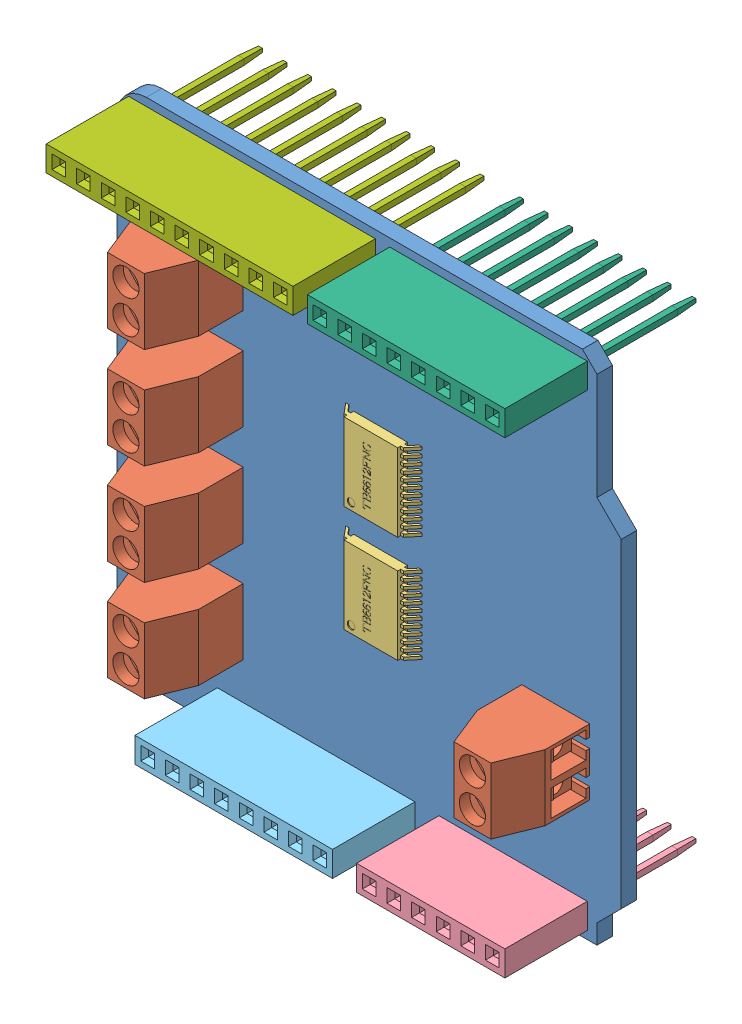
SolidWorks assembly Shield Quad Motor driver TB6612FNG, configuration Défaut. Lengths in mm.
Overall size (52 52.5 20.9).
12 component instances, 7 part files, 33 mates.
Components (placement in the parent):
- Shield Quad Motor - plaque-1: Shield Quad Motor - plaque [Défaut] at (1.0198 -6.275 51.7045) size (52 52.5 1.6)
- bornier double-1: bornier double [Défaut] at (-20.6895 19.3651 53.3045) x (0 -1 0) z (-1 0 0) size (6.8 12.2 7)
- bornier double-2: bornier double [Défaut] at (-20.6895 8.9651 53.3045) x (0 -1 0) z (-1 0 0) size (6.8 12.2 7)
- bornier double-3: bornier double [Défaut] at (-20.6895 -1.4349 53.3045) x (0 -1 0) z (-1 0 0) size (6.8 12.2 7)
- bornier double-4: bornier double [Défaut] at (-20.6895 -11.8349 53.3045) x (0 -1 0) z (-1 0 0) size (6.8 12.2 7)
- bornier double-5: bornier double [Défaut] at (22.0605 -13.2893 53.3045) x (0 1 0) z (1 0 0) size (6.8 12.2 7)
- Microcontroller TB6612FNG-1: Microcontroller TB6612FNG [Défaut] at (0.8257 5.6107 53.6445) x (0 1 0) z (0 0 1) size (8 8.26 1.72)
- Microcontroller TB6612FNG-2: Microcontroller TB6612FNG [Défaut] at (0.8257 -5.3893 53.6445) x (0 1 0) z (0 0 1) size (8 8.26 1.72)
- broche wrapping 6F-1: broche wrapping 6F [Défaut] at (7.8105 -23.7693 53.3045) x (1 0 0) z (0 -1 0) size (15.3 20.8 2.6)
- broche wrapping 8F-rouge-1: broche wrapping 8F-rouge [Défaut] at (-15.0495 -23.7693 53.3045) x (1 0 0) z (0 -1 0) size (20.38 20.8 2.6)
- broche wrapping 8F-vert-1: broche wrapping 8F-vert [Défaut] at (2.7305 24.4951 53.3045) x (1 0 0) z (0 -1 0) size (20.38 20.8 2.6)
- broche wrapping 10F-vert-1: broche wrapping 10F-vert [Défaut] at (-1.3495 24.4951 53.3045) x (-1 0 0) z (0 1 0) size (25.46 20.8 2.6)
Mates (geometry in assembly coordinates):
- Coïncidente1: coincident anti-aligned: plane of Plaque de base-1 through (-23.6895 23.6151 53.3045) normal (0 0 1); plane of bornier double-1 through (-13.6895 15.9651 53.3045) normal (0 0 -1)
- Parallèle1: parallel aligned: plane of Plaque de base-1 through (-26.6895 23.6151 53.3045) normal (-1 0 0); plane of bornier double-1 through (-20.6895 15.9651 53.3045) normal (-1 0 0)
- Coïncidente3: coincident anti-aligned: plane of Plaque de base-1 through (-23.6895 23.6151 53.3045) normal (0 0 1); plane of bornier double-2 through (-13.6895 5.5651 53.3045) normal (0 0 -1)
- Distance1: distance = 6 mm aligned: plane of bornier double-1 through (-20.6895 15.9651 53.3045) normal (-1 0 0); plane of Plaque de base-1 through (-26.6895 23.6151 53.3045) normal (-1 0 0)
- Distance2: distance = 7.25 mm aligned: plane of bornier double-1 through (-20.6895 19.3651 53.3045) normal (0 1 0); plane of Plaque de base-1 through (-23.6895 26.6151 53.3045) normal (0 1 0)
- Coïncidente7: coincident aligned: plane of bornier double-1 through (-20.6895 15.9651 53.3045) normal (-1 0 0); plane of bornier double-2 through (-20.6895 5.5651 53.3045) normal (-1 0 0)
- Distance3: distance = 3.6 mm anti-aligned: plane of bornier double-2 through (-20.6895 8.9651 53.3045) normal (0 1 0); plane of bornier double-1 through (-20.6895 12.5651 53.3045) normal (0 -1 0)
- Coïncidente9: coincident anti-aligned: plane of Plaque de base-1 through (-23.6895 23.6151 53.3045) normal (0 0 1); plane of bornier double-3 through (-13.6895 -4.8349 53.3045) normal (0 0 -1)
- Distance4: distance = 3.6 mm anti-aligned: plane of bornier double-2 through (-20.6895 2.1651 53.3045) normal (0 -1 0); plane of bornier double-3 through (-20.6895 -1.4349 53.3045) normal (0 1 0)
- Coïncidente11: coincident aligned: plane of bornier double-2 through (-20.6895 5.5651 53.3045) normal (-1 0 0); plane of bornier double-3 through (-20.6895 -4.8349 53.3045) normal (-1 0 0)
- Coïncidente12: coincident aligned: plane of bornier double-3 through (-20.6895 -4.8349 53.3045) normal (-1 0 0); plane of bornier double-4 through (-20.6895 -15.2349 53.3045) normal (-1 0 0)
- Coïncidente13: coincident anti-aligned: plane of Plaque de base-1 through (-23.6895 23.6151 53.3045) normal (0 0 1); plane of bornier double-4 through (-13.6895 -15.2349 53.3045) normal (0 0 -1)
- Distance5: distance = 3.6 mm anti-aligned: plane of bornier double-3 through (-20.6895 -8.2349 53.3045) normal (0 -1 0); plane of bornier double-4 through (-20.6895 -11.8349 53.3045) normal (0 1 0)
- Coïncidente15: coincident anti-aligned: plane of Plaque de base-1 through (-23.6895 23.6151 53.3045) normal (0 0 1); plane of bornier double-5 through (15.0605 -9.8893 53.3045) normal (0 0 -1)
- Distance6: distance = 12.6 mm aligned: plane of bornier double-5 through (22.0605 -13.2893 53.3045) normal (0 -1 0); plane of Plaque de base-1 through (22.8105 -25.8893 53.3045) normal (0 -1 0)
- Distance7: distance = 3.25 mm aligned: plane of bornier double-5 through (22.0605 -9.8893 53.3045) normal (1 0 0); plane of Plaque de base-1 through (25.3105 11.6151 53.3045) normal (1 0 0)
- Distance8: distance = 27.5 mm aligned: plane of Microcontroller TB6612FNG-1 through (-1.9443 1.6107 54.6445) normal (0 -1 0); plane of Plaque de base-1 through (22.8105 -25.8893 53.3045) normal (0 -1 0)
- Coïncidente20: coincident aligned: plane of Plaque de base-1 through (-23.6895 23.6151 53.3045) normal (0 0 1); plane of Microcontroller TB6612FNG-1 through (-3.3043 1.9107 53.3045) normal (0 0 1)
- Coïncidente21: coincident aligned: plane of Microcontroller TB6612FNG-1 through (0.8257 5.6107 54.6445) normal (0 0 1); plane of Microcontroller TB6612FNG-2 through (0.8257 -5.3893 54.6445) normal (0 0 1)
- Coïncidente22: coincident aligned: plane of Microcontroller TB6612FNG-1 through (-1.9443 1.6107 54.6445) normal (-1 0 0); plane of Microcontroller TB6612FNG-2 through (-1.9443 -9.3893 54.6445) normal (-1 0 0)
- Distance10: distance = 3 mm anti-aligned: plane of Microcontroller TB6612FNG-1 through (-1.9443 1.6107 54.6445) normal (0 -1 0); plane of Microcontroller TB6612FNG-2 through (-1.9443 -1.3893 54.6445) normal (0 1 0)
- Distance11: distance = 0.82 mm aligned: plane of broche wrapping 6F-1 through (6.5105 -25.0693 61.8045) normal (0 -1 0); plane of Plaque de base-1 through (22.8105 -25.8893 53.3045) normal (0 -1 0)
- Distance12: distance = 3.5 mm aligned: plane of broche wrapping 6F-1 through (21.8105 -25.0693 61.8045) normal (1 0 0); plane of Plaque de base-1 through (25.3105 11.6151 53.3045) normal (1 0 0)
- Coïncidente29: coincident aligned: plane of broche wrapping 6F-1 through (6.5105 -25.0693 61.8045) normal (0 -1 0); plane of broche wrapping 8F-rouge-1 through (-16.3495 -25.0693 61.8045) normal (0 -1 0)
- Coïncidente30: coincident aligned: plane of broche wrapping 6F-1 through (7.8105 -23.7693 61.8045) normal (0 0 1); plane of broche wrapping 8F-rouge-1 through (-15.0495 -23.7693 61.8045) normal (0 0 1)
- Distance13: distance = 2.48 mm anti-aligned: plane of broche wrapping 8F-rouge-1 through (4.0305 -25.0693 61.8045) normal (1 0 0); plane of broche wrapping 6F-1 through (6.5105 -25.0693 61.8045) normal (-1 0 0)
- Distance14: distance = 0.82 mm aligned: plane of broche wrapping 8F-vert-1 through (1.4305 25.7951 61.8045) normal (0 1 0); plane of Plaque de base-1 through (-23.6895 26.6151 53.3045) normal (0 1 0)
- Coïncidente34: coincident aligned: plane of broche wrapping 6F-1 through (21.8105 -25.0693 61.8045) normal (1 0 0); plane of broche wrapping 8F-vert-1 through (21.8105 23.1951 61.8045) normal (1 0 0)
- Coïncidente35: coincident aligned: plane of broche wrapping 8F-vert-1 through (2.7305 24.4951 61.8045) normal (0 0 1); plane of broche wrapping 10F-vert-1 through (-0.8695 24.4951 61.8045) normal (0 0 1)
- Coïncidente36: coincident aligned: plane of broche wrapping 8F-vert-1 through (1.4305 25.7951 61.8045) normal (0 1 0); plane of broche wrapping 10F-vert-1 through (0.4305 25.7951 61.8045) normal (0 1 0)
- Distance15: distance = 1.48 mm anti-aligned: plane of broche wrapping 10F-vert-1 through (-0.0495 25.7951 61.8045) normal (1 0 0); plane of broche wrapping 8F-vert-1 through (1.4305 23.1951 61.8045) normal (-1 0 0)
- Coïncidente37: coincident anti-aligned: plane of Plaque de base-1 through (-23.6895 23.6151 51.7045) normal (0 0 -1); plane of broche wrapping 6F-1 through (20.5105 -23.7693 51.7045) normal (0 0 1)
- Coïncidente38: coincident aligned: plane of Plaque de base-1 through (-23.6895 23.6151 51.7045) normal (0 0 -1); circle of broche wrapping 8F-vert-1
